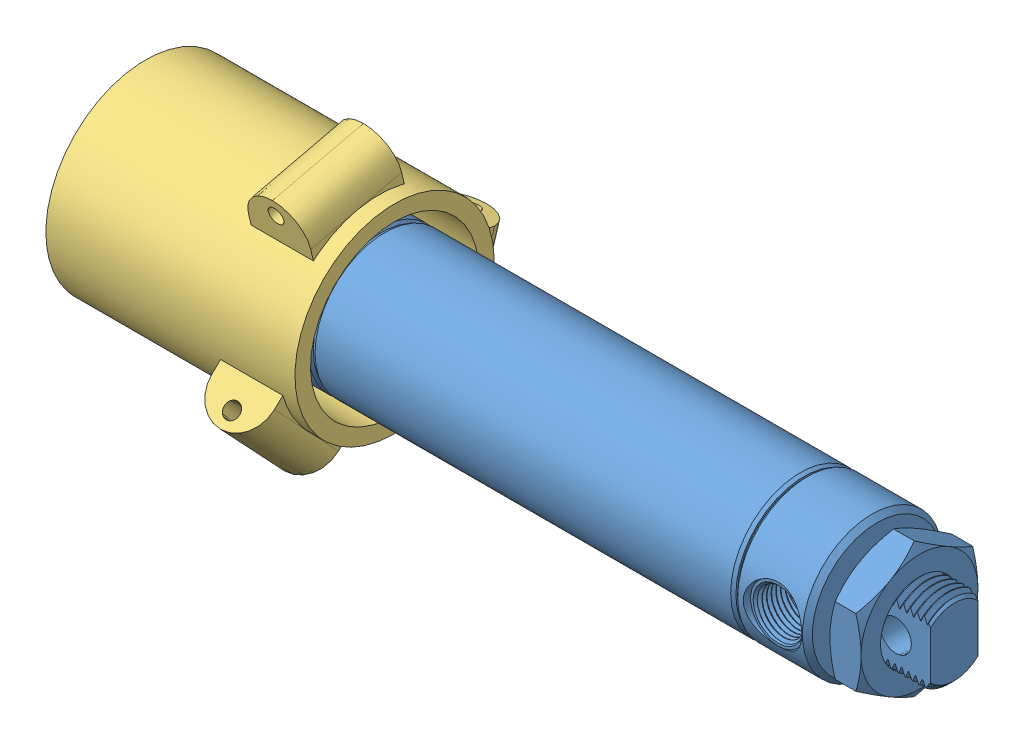
SolidWorks assembly Piston Assem, configuration Default. Lengths in mm.
3 component instances, 3 part files, 4 mates.
Components (placement in the parent):
- Piston Body-1: Piston Body [6498K654] at (48.3607 91.1672 114.2196) size (153.11 28.45 28.45)
- Piston Shaft-1: Piston Shaft [6498K654] at (48.3607 91.1672 114.2196) x (1 0 0) z (0 -0.982174 -0.187974) size (70.22 8.18 8.17)
- Piston Cup CORRECT-2: Piston Cup CORRECT [Default] at (-32.5383 91.1672 114.2196) x (0 -0.728683 -0.684851) z (0 -0.684851 0.728683) size (55.72 50.8 48.25)
Mates (geometry in assembly coordinates):
- Concentric1: concentric: circle of Piston Body-1; cylinder of Piston Shaft-1 through (-23.0133 91.1672 114.2196) axis (-1 0 0) radius 3.9624
- LimitDistance1: limit distance = 15.748 mm: plane of Piston Body-1 through (-19.9653 91.1672 114.2196) normal (-1 0 0); plane of Piston Shaft-1 through (-35.7133 91.9133 110.3216) normal (-1 0 0)
- Concentric4: concentric: circle of Piston Shaft-1; circle of Piston Cup CORRECT-2
- Distance1: distance = 3.175 mm: plane of Piston Cup CORRECT-2 through (-32.5383 91.1672 114.2196) normal (-1 0 0); plane of Piston Shaft-1 through (-35.7133 91.9133 110.3216) normal (-1 0 0)
